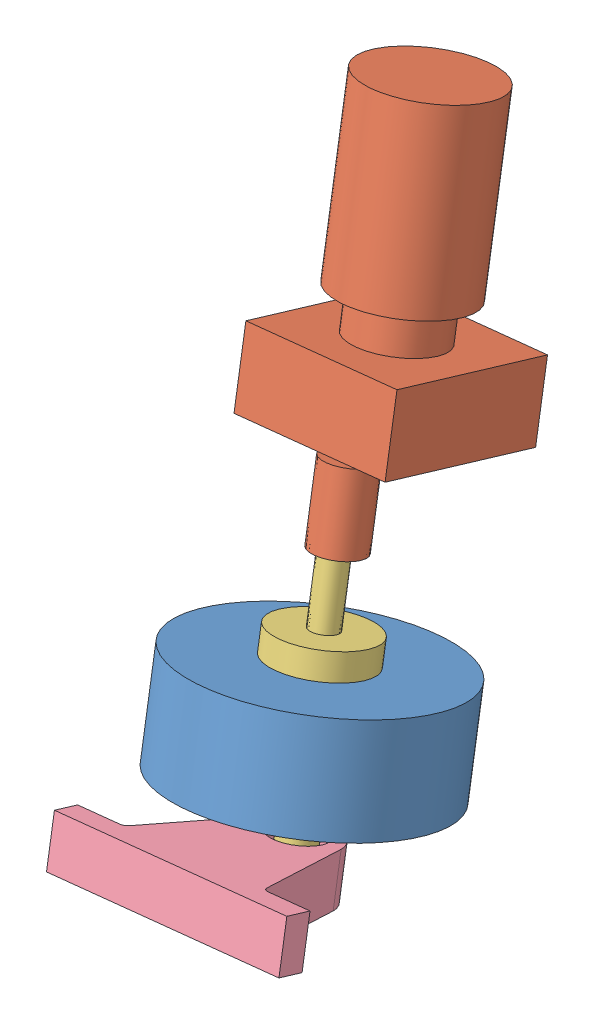
SolidWorks assembly Wheel_sys_lower, configuration Default. Lengths in mm.
Overall size (141.79 280.46 162.59).
4 component instances, 4 part files, 8 mates.
Components (placement in the parent):
- omni-1: omni [Default] at (-77.0455 69.9199 150.3063) x (0.545954 -0.173862 -0.819577) z (0.831792 0.229571 0.50539) size (100 40 100)
- motor-1: motor [Default] at (-76.5038 184.1966 116.3052) x (0.994562 0.104149 0) z (-0.028115 0.268484 0.962874) size (65 158 65)
- shaft-1: shaft [Default] at (-87.3634 168.4493 120.2645) x (-0.994562 -0.104149 0) z (-0.028115 0.268484 0.962874) size (38.13 139.7 38.13)
- support_lower_wheel-1: support_lower_wheel [Default] at (-76.2241 54.2728 211.6456) x (0.994562 0.104149 0) z (-0.100283 0.957637 -0.269952) size (100 70 20)
Mates (geometry in assembly coordinates):
- Coincident4: coincident anti-aligned: plane of motor-1 through (-54.7689 167.353 124.8632) normal (0.028115 -0.268484 -0.962874); plane of shaft-1 through (-79.3808 143.1087 130.9047) normal (-0.028115 0.268484 0.962874)
- Coincident5: coincident anti-aligned: plane of motor-1 through (-47.2459 145.7662 128.3946) normal (0.100283 -0.957637 0.269952); plane of shaft-1 through (-84.5615 141.6929 127.807) normal (-0.100283 0.957637 -0.269952)
- Concentric5: concentric aligned: cylinder of omni-1 through (-77.0455 69.9199 150.3063) axis (0.100283 -0.957637 0.269952) radius 6.5; circle of shaft-1
- Concentric6: concentric anti-aligned: circle of shaft-1; circle of support_lower_wheel-1
- Parallel1: parallel aligned: plane of motor-1 through (-75.3575 222.1822 139.5001) normal (-0.028115 0.268484 0.962874); plane of support_lower_wheel-1 through (-76.2241 54.2728 211.6456) normal (-0.028115 0.268484 0.962874)
- Coincident8: coincident anti-aligned: plane of omni-1 through (-81.0568 108.2254 139.5082) normal (-0.100283 0.957637 -0.269952); plane of shaft-1 through (-81.0568 108.2254 139.5082) normal (0.100283 -0.957637 0.269952)
- Coincident11: coincident aligned: plane of shaft-1 through (-73.4153 35.2534 160.0786) normal (0.100283 -0.957637 0.269952); plane of support_lower_wheel-1 through (-124.404 42.0842 203.2518) normal (0.100283 -0.957637 0.269952)
- Coincident14: coincident anti-aligned: line of motor-1 through (-81.6251 164.5406 124.8632) axis (0.100283 -0.957637 0.269952); line of shaft-1 through (-79.3808 143.1087 130.9047) axis (-0.100283 0.957637 -0.269952)
